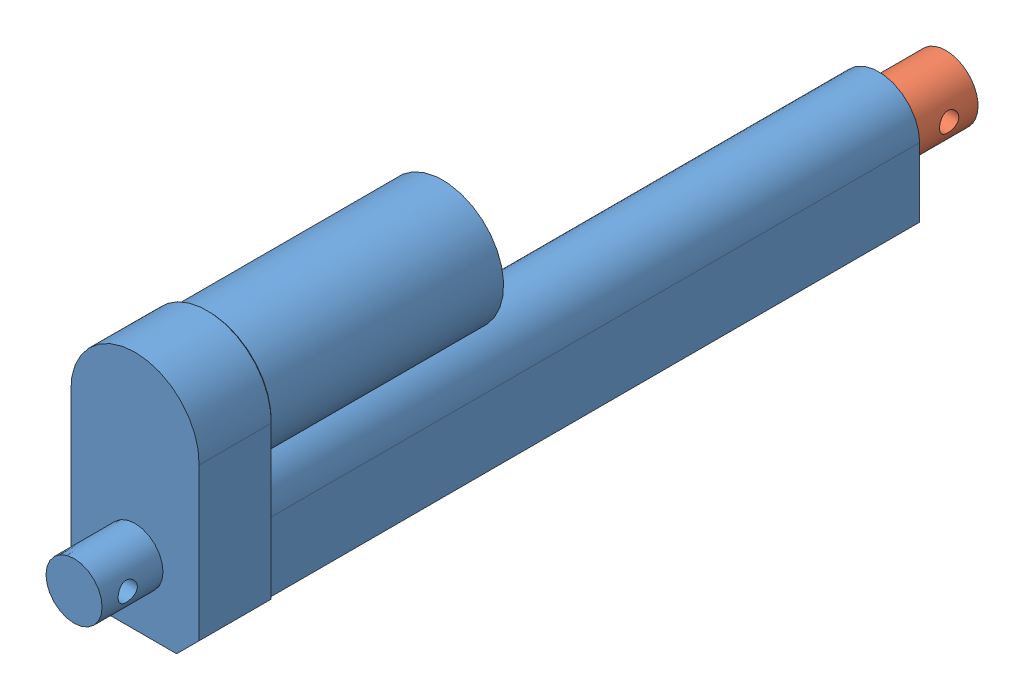
SolidWorks assembly Motor150, configuration Default. Lengths in mm.
Overall size (40.01 75 272).
2 component instances, 2 part files, 3 mates.
Components (placement in the parent):
- motor150-1: motor150 [Predeterminado] at (96.608 131.4242 267.3633) x (1 0 0) z (0 -1 0) size (40.01 251 75)
- eje150-1: eje150 [Predeterminado] at (96.608 124.1742 58.3633) x (-1 0 0) z (0 1 0) size (20 171 20)
Mates (geometry in assembly coordinates):
- Concentric1: concentric anti-aligned: cylinder of motor150-1 through (96.608 124.1742 208.3633) axis (0 0 -1) radius 10; cylinder of eje150-1 through (96.608 124.1742 37.3633) axis (0 0 1) radius 10
- LimitDistance1: limit distance = 0 mm anti-aligned: plane of motor150-1 through (96.608 124.1742 208.3633) normal (0 0 -1); plane of eje150-1 through (96.608 124.1742 208.3633) normal (0 0 1)
- Parallel1: parallel anti-aligned: cylinder of motor150-1 through (84.108 124.1742 301.3633) axis (1 0 0) radius 3; cylinder of eje150-1 through (109.108 124.1742 46.3633) axis (-1 0 0) radius 3
